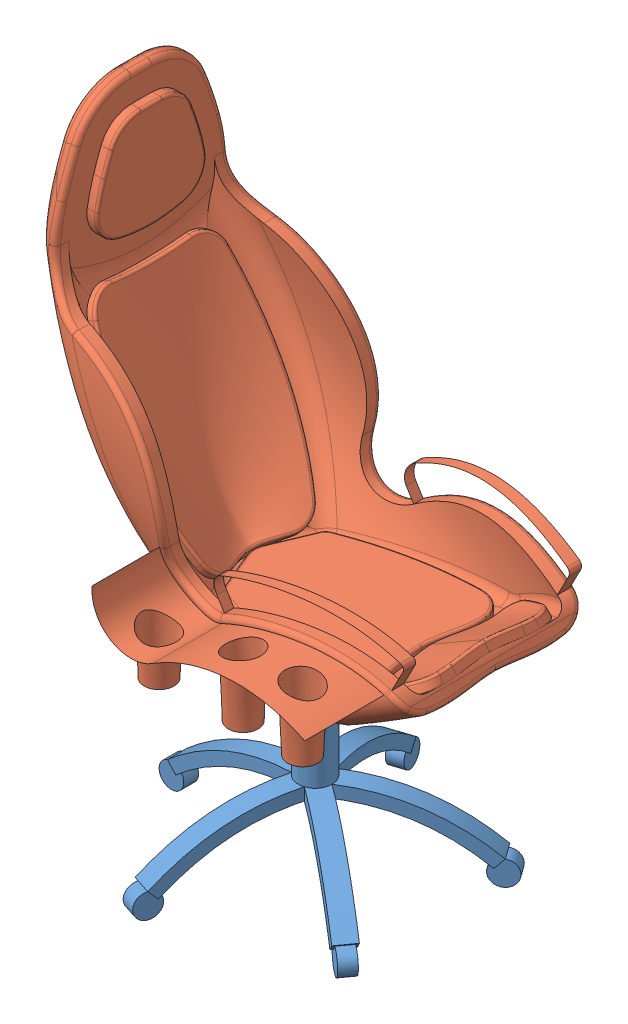
SolidWorks assembly Chair Assembly, configuration Default. Lengths in mm.
Overall size (807.46 1226.11 639.18).
2 component instances, 2 part files, 1 mates.
Components (placement in the parent):
- Base-1: Base [Default] at (398.5759 -199.7027 436.9375) size (551.96 444.33 580.37)
- Seat-1: Seat [Default] at (294.3935 100.2973 435.9265) size (807.46 788.45 603.12)
Mates (geometry in assembly coordinates):
- Coincident1: coincident: plane of assembly; plane of assembly; plane of Base-1 through (398.5759 100.2973 436.9375) normal (0 1 0); plane of Seat-1 through (576.9147 100.2973 435.9265) normal (0 -1 0)
